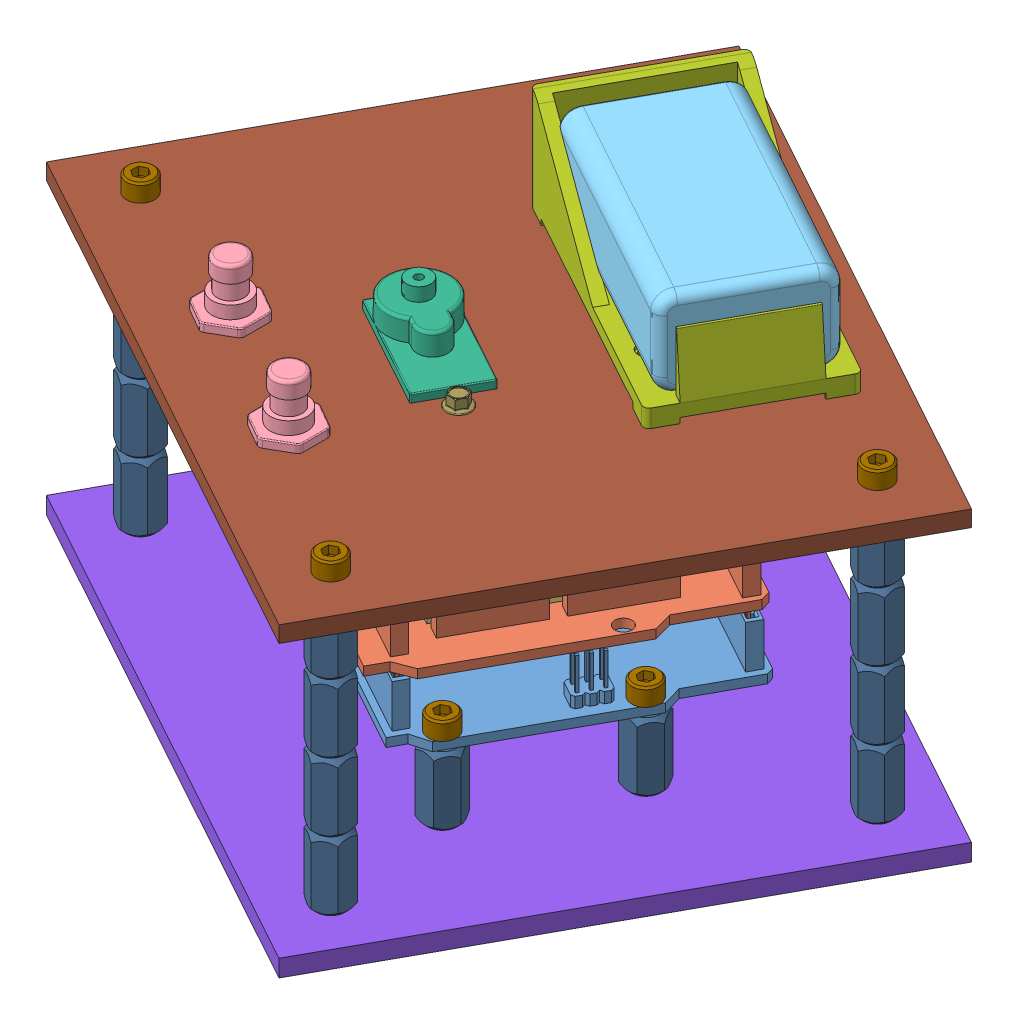
SolidWorks assembly Assembly FinalV2, configuration Default. Lengths in mm.
Overall size (142.18 79.59 136.27).
50 component instances, 12 part files, 102 mates.
Components (placement in the parent):
- ArduinoUno-2: ArduinoUno [Default] at (-58.3842 6.7583 120.4555) x (0.876025 0 0.482266) z (-0.482266 0 0.876025) size (74.8 12.1 53.3)
- Prototyping Shield-Simple-1: Prototyping Shield-Simple [Default] at (-68.6916 -16.1579 180.3995) x (-0.876025 0 -0.482266) z (0.482266 0 -0.876025) size (68 18.92 56)
  - Arduino Prototyping Shield-1: Arduino Prototyping Shield [Default] at (18.3696 35.0162 55.7334) size (68 18.92 56)
  - MiniBreadboard-Simple-1: MiniBreadboard-Simple [Default] at (16.6696 36.6462 55.7334) x (0 0 1) z (-1 0 0) size (34.6 8.15 45.6)
- Panel Mount Pushbutton-1: Panel Mount Pushbutton [Default] at (-85.6604 36.7333 145.3581) size (9.91 29 11.13)
- Panel Mount Pushbutton-2: Panel Mount Pushbutton [Default] at (-61.5698 36.7333 158.6204) size (9.91 29 11.13)
- 9V Battery 2-1: 9V Battery 2 [Default] at (-29.0026 45.2936 106.7603) x (0.482266 0 -0.876025) z (0 1 0) size (25.91 48.13 16.26)
- Micro Servo FS90R Continuous-1: Micro Servo FS90R Continuous [Valor predeterminado] at (-61.5234 42.8583 132.3784) x (0.876025 0 0.482266) z (-0.482266 0 0.876025) size (32 29 12)
- 9V Battery Holder-2: 9V Battery Holder [Default] at (-44.7152 48.8583 99.4932) x (0.876025 0 0.482266) z (0 1 0) size (53.5 30 19.31)
- Acrylic-1: Acrylic [Default] at (-56.2866 -9.1217 122.8659) x (0.876025 0 0.482266) z (-0.482266 0 0.876025) size (110 3.18 95)
- socket head cap screw_ai-6: socket head cap screw_ai [HX-SHCS 0.125-44x0.25x0.25-N] at (-86.6754 -12.2967 132.4484) x (0 1 0) z (0 0 1) size (9.53 5.21 5.21)
- socket head cap screw_ai-7: socket head cap screw_ai [HX-SHCS 0.125-44x0.25x0.25-N] at (-61.9803 -12.2967 90.9081) x (0 1 0) z (0 0 1) size (9.53 5.21 5.21)
- socket head cap screw_ai-8: socket head cap screw_ai [HX-SHCS 0.125-44x0.25x0.25-N] at (-24.8569 -12.2967 128.8104) x (0 1 0) z (0 0 1) size (9.53 5.21 5.21)
- socket head cap screw_ai-9: socket head cap screw_ai [HX-SHCS 0.125-44x0.25x0.25-N] at (-38.3121 -12.2967 153.2514) x (0 1 0) z (0 0 1) size (9.53 5.21 5.21)
- 25x.5 Aluminum Hex Female Female Standoff-1: 25x.5 Aluminum Hex Female Female Standoff [Default] at (-61.9803 0.4083 90.9081) x (-0.837169 0 -0.546944) z (0 -1 0) size (6.35 8.06 12.7)
- 25x.5 Aluminum Hex Female Female Standoff-2: 25x.5 Aluminum Hex Female Female Standoff [Default] at (-86.6754 0.4083 132.4484) x (-0.837169 0 -0.546944) z (0 -1 0) size (6.35 8.06 12.7)
- 25x.5 Aluminum Hex Female Female Standoff-3: 25x.5 Aluminum Hex Female Female Standoff [Default] at (-38.3121 0.4083 153.2514) x (-0.837169 0 -0.546944) z (0 -1 0) size (6.35 8.06 12.7)
- 25x.5 Aluminum Hex Female Female Standoff-4: 25x.5 Aluminum Hex Female Female Standoff [Default] at (-34.9505 0.4083 177.4188) x (1 0 0) z (0 -1 0) size (6.35 8.06 12.7)
- 25x.5 Aluminum Hex Female Female Standoff-5: 25x.5 Aluminum Hex Female Female Standoff [Default] at (-24.8569 0.4083 128.8104) x (-0.837169 0 -0.546944) z (0 -1 0) size (6.35 8.06 12.7)
- socket head cap screw_ai-11: socket head cap screw_ai [HX-SHCS 0.125-44x0.25x0.25-N] at (-24.8569 11.5333 128.8104) x (0 -1 0) z (0.546944 0 -0.837169) size (9.53 5.21 5.21)
- socket head cap screw_ai-12: socket head cap screw_ai [HX-SHCS 0.125-44x0.25x0.25-N] at (-38.3121 11.5333 153.2514) x (0 -1 0) z (0.546944 0 -0.837169) size (9.53 5.21 5.21)
- socket head cap screw_ai-13: socket head cap screw_ai [HX-SHCS 0.125-44x0.25x0.25-N] at (-86.6754 11.5333 132.4484) x (0 -1 0) z (0.546944 0 -0.837169) size (9.53 5.21 5.21)
- socket head cap screw_ai-14: socket head cap screw_ai [HX-SHCS 0.125-44x0.25x0.25-N] at (-61.9803 11.5333 90.9081) x (0 -1 0) z (0.546944 0 -0.837169) size (9.53 5.21 5.21)
- socket head cap screw_ai-17: socket head cap screw_ai [HX-SHCS 0.125-44x0.25x0.25-N] at (-61.4854 15.6833 91.0663) x (0 1 0) z (0 0 1) size (9.53 5.21 5.21)
- socket head cap screw_ai-18: socket head cap screw_ai [HX-SHCS 0.125-44x0.25x0.25-N] at (-34.9505 -12.2967 177.4188) x (0 1 0) z (0 0 1) size (9.53 5.21 5.21)
- socket head cap screw_ai-19: socket head cap screw_ai [HX-SHCS 0.125-44x0.25x0.25-N] at (1.2195 -12.2967 111.717) x (0 1 0) z (0 0 1) size (9.53 5.21 5.21)
- socket head cap screw_ai-20: socket head cap screw_ai [HX-SHCS 0.125-44x0.25x0.25-N] at (-77.6228 -12.2967 68.313) x (0 1 0) z (0 0 1) size (9.53 5.21 5.21)
- socket head cap screw_ai-21: socket head cap screw_ai [HX-SHCS 0.125-44x0.25x0.25-N] at (-113.7927 -12.2967 134.0149) x (0 1 0) z (0 0 1) size (9.53 5.21 5.21)
- 25x.5 Aluminum Hex Female Female Standoff-6: 25x.5 Aluminum Hex Female Female Standoff [Default] at (1.2195 0.4083 111.717) x (1 0 0) z (0 -1 0) size (6.35 8.06 12.7)
- 25x.5 Aluminum Hex Female Female Standoff-7: 25x.5 Aluminum Hex Female Female Standoff [Default] at (-113.7927 0.4083 134.0149) x (1 0 0) z (0 -1 0) size (6.35 8.06 12.7)
- 25x.5 Aluminum Hex Female Female Standoff-8: 25x.5 Aluminum Hex Female Female Standoff [Default] at (-77.6228 0.4083 68.313) x (1 0 0) z (0 -1 0) size (6.35 8.06 12.7)
- 25x.5 Aluminum Hex Female Female Standoff-9: 25x.5 Aluminum Hex Female Female Standoff [Default] at (-34.9505 38.5083 177.4188) x (1 0 0) z (0 -1 0) size (6.35 8.06 12.7)
- 25x.5 Aluminum Hex Female Female Standoff-10: 25x.5 Aluminum Hex Female Female Standoff [Default] at (1.2195 25.8083 111.717) x (1 0 0) z (0 -1 0) size (6.35 8.06 12.7)
- 25x.5 Aluminum Hex Female Female Standoff-11: 25x.5 Aluminum Hex Female Female Standoff [Default] at (-34.9505 13.1083 177.4188) x (1 0 0) z (0 -1 0) size (6.35 8.06 12.7)
- 25x.5 Aluminum Hex Female Female Standoff-12: 25x.5 Aluminum Hex Female Female Standoff [Default] at (1.2195 13.1083 111.717) x (1 0 0) z (0 -1 0) size (6.35 8.06 12.7)
- 25x.5 Aluminum Hex Female Female Standoff-13: 25x.5 Aluminum Hex Female Female Standoff [Default] at (-34.9505 25.8083 177.4188) x (1 0 0) z (0 -1 0) size (6.35 8.06 12.7)
- 25x.5 Aluminum Hex Female Female Standoff-15: 25x.5 Aluminum Hex Female Female Standoff [Default] at (1.2195 38.5083 111.717) x (1 0 0) z (0 -1 0) size (6.35 8.06 12.7)
- 25x.5 Aluminum Hex Female Female Standoff-16: 25x.5 Aluminum Hex Female Female Standoff [Default] at (-113.7927 25.8083 134.0149) x (1 0 0) z (0 -1 0) size (6.35 8.06 12.7)
- 25x.5 Aluminum Hex Female Female Standoff-17: 25x.5 Aluminum Hex Female Female Standoff [Default] at (-113.7927 38.5083 134.0149) x (1 0 0) z (0 -1 0) size (6.35 8.06 12.7)
- 25x.5 Aluminum Hex Female Female Standoff-18: 25x.5 Aluminum Hex Female Female Standoff [Default] at (-77.6228 25.8083 68.313) x (1 0 0) z (0 -1 0) size (6.35 8.06 12.7)
- 25x.5 Aluminum Hex Female Female Standoff-19: 25x.5 Aluminum Hex Female Female Standoff [Default] at (-77.6228 13.1083 68.313) x (1 0 0) z (0 -1 0) size (6.35 8.06 12.7)
- 25x.5 Aluminum Hex Female Female Standoff-20: 25x.5 Aluminum Hex Female Female Standoff [Default] at (-113.7927 13.1083 134.0149) x (1 0 0) z (0 -1 0) size (6.35 8.06 12.7)
- 25x.5 Aluminum Hex Female Female Standoff-21: 25x.5 Aluminum Hex Female Female Standoff [Default] at (-77.6228 38.5083 68.313) x (1 0 0) z (0 -1 0) size (6.35 8.06 12.7)
- Topv4-1: Topv4 [Default] at (-56.2866 44.8583 122.8659) x (0.876025 0 0.482266) z (-0.482266 0 0.876025) size (110 3 95)
- socket head cap screw_ai-22: socket head cap screw_ai [HX-SHCS 0.125-44x0.25x0.25-N] at (-34.9505 51.0333 177.4188) x (0 -1 0) z (0.546944 0 -0.837169) size (9.53 5.21 5.21)
- socket head cap screw_ai-23: socket head cap screw_ai [HX-SHCS 0.125-44x0.25x0.25-N] at (1.2195 51.0333 111.717) x (0 -1 0) z (0.546944 0 -0.837169) size (9.53 5.21 5.21)
- socket head cap screw_ai-24: socket head cap screw_ai [HX-SHCS 0.125-44x0.25x0.25-N] at (-77.6228 51.0333 68.313) x (0 -1 0) z (0.546944 0 -0.837169) size (9.53 5.21 5.21)
- socket head cap screw_ai-25: socket head cap screw_ai [HX-SHCS 0.125-44x0.25x0.25-N] at (-113.7927 51.0333 134.0149) x (0 -1 0) z (0.546944 0 -0.837169) size (9.53 5.21 5.21)
- hex flange machine screw_am-1: hex flange machine screw_am [B18.6.7M - M2 x 0.4 x 6 Indented HFMS --6N] at (-73.4592 50.0583 125.8075) x (0 -1 0) z (0 0 1) size (8.2 4.5 4.5)
- hex flange machine screw_am-2: hex flange machine screw_am [B18.6.7M - M2 x 0.4 x 6 Indented HFMS --6N] at (-49.5876 50.0583 138.9493) x (0 -1 0) z (0 0 1) size (8.2 4.5 4.5)
Mates (geometry in assembly coordinates):
- Coincident11: coincident anti-aligned: plane of ArduinoUno-2 through (-89.9996 18.8583 96.6011) normal (0 1 0); plane of Prototyping Shield-Simple-1/Arduino Prototyping Shield-1 through (-74.1869 18.8583 81.7909) normal (0 -1 0)
- Coincident12: coincident anti-aligned: plane of ArduinoUno-2 through (-43.5141 16.3583 156.8944) normal (0.482266 0 -0.876025); plane of Prototyping Shield-Simple-1/Arduino Prototyping Shield-1 through (-43.5141 10.1083 156.8944) normal (-0.482266 0 0.876025)
- Coincident13: coincident anti-aligned: plane of ArduinoUno-2 through (-43.5141 16.3583 156.8944) normal (-0.876025 0 -0.482266); plane of Prototyping Shield-Simple-1/Arduino Prototyping Shield-1 through (-43.2729 10.1083 156.4564) normal (0.876025 0 0.482266)
- Parallel1: parallel aligned: plane of ArduinoUno-2 through (-99.6631 8.3583 127.0107) normal (-0.876025 0 -0.482266); plane of Prototyping Shield-Simple-1/Arduino Prototyping Shield-1 through (-101.1938 20.4883 130.8483) normal (-0.876025 0 -0.482266)
- Coincident15: coincident anti-aligned: plane of 9V Battery 2-1 through (-29.2808 67.2977 122.7773) normal (0.876025 0 0.482266); plane of 9V Battery Holder-2 through (-27.8562 59.1697 120.1895) normal (-0.876025 0 -0.482266)
- Concentric1: concentric anti-aligned: cylinder of 9V Battery 2-1 through (-59.0217 59.1697 84.3685) axis (0.876025 0 0.482266) radius 2.921; cylinder of 9V Battery Holder-2 through (-60.4335 59.1697 83.5913) axis (-0.876025 0 -0.482266) radius 2.5
- Concentric7: concentric anti-aligned: cylinder of Acrylic-1 through (-86.6754 -9.1217 132.4484) axis (0 1 0) radius 1.6; cylinder of socket head cap screw_ai-6 through (-86.6754 -44.0467 132.4484) axis (0 -1 0) radius 2.6035
- Coincident21: coincident anti-aligned: plane of Acrylic-1 through (-56.2866 -9.1217 122.8659) normal (0 -1 0); plane of socket head cap screw_ai-6 through (-89.2789 -9.1217 132.4484) normal (0 1 0)
- Concentric8: concentric anti-aligned: cylinder of Acrylic-1 through (-61.9803 -9.1217 90.9081) axis (0 1 0) radius 1.6; cylinder of socket head cap screw_ai-7 through (-61.9803 -44.0467 90.9081) axis (0 -1 0) radius 2.6035
- Coincident22: coincident anti-aligned: plane of Acrylic-1 through (-56.2866 -9.1217 122.8659) normal (0 -1 0); plane of socket head cap screw_ai-7 through (-64.5838 -9.1217 90.9081) normal (0 1 0)
- Concentric91: concentric anti-aligned: cylinder of Acrylic-1 through (-24.8569 -9.1217 128.8104) axis (0 1 0) radius 1.6; cylinder of socket head cap screw_ai-8 through (-24.8569 -44.0467 128.8104) axis (0 -1 0) radius 2.6035
- Coincident231: coincident anti-aligned: plane of Acrylic-1 through (-56.2866 -9.1217 122.8659) normal (0 -1 0); plane of socket head cap screw_ai-8 through (-27.4604 -9.1217 128.8104) normal (0 1 0)
- Concentric10: concentric anti-aligned: cylinder of Acrylic-1 through (-38.3121 -9.1217 153.2514) axis (0 1 0) radius 1.6; cylinder of socket head cap screw_ai-9 through (-38.3121 -44.0467 153.2514) axis (0 -1 0) radius 2.6035
- Coincident24: coincident anti-aligned: plane of Acrylic-1 through (-56.2866 -9.1217 122.8659) normal (0 -1 0); plane of socket head cap screw_ai-9 through (-40.9156 -9.1217 153.2514) normal (0 1 0)
- Concentric12: concentric aligned: cylinder of ArduinoUno-2 through (-24.8569 8.3583 128.8104) axis (0 -1 0) radius 1.6; cylinder of socket head cap screw_ai-8 through (-24.8569 -44.0467 128.8104) axis (0 -1 0) radius 1.5875
- Concentric13: concentric aligned: cylinder of ArduinoUno-2 through (-38.3121 8.3583 153.2514) axis (0 -1 0) radius 1.6; cylinder of socket head cap screw_ai-9 through (-38.3121 -44.0467 153.2514) axis (0 -1 0) radius 1.5875
- Concentric15: concentric aligned: cylinder of socket head cap screw_ai-6 through (-86.6754 -44.0467 132.4484) axis (0 -1 0) radius 1.5875; cylinder of 25x.5 Aluminum Hex Female Female Standoff-2 through (-86.6754 -5.9417 132.4484) axis (0 -1 0) radius 1.0287
- Coincident25: coincident anti-aligned: plane of Acrylic-1 through (-56.2866 -5.9417 122.8659) normal (0 1 0); plane of 25x.5 Aluminum Hex Female Female Standoff-2 through (-86.6754 -5.9417 132.4484) normal (0 -1 0)
- Concentric16: concentric aligned: cylinder of socket head cap screw_ai-9 through (-38.3121 -44.0467 153.2514) axis (0 -1 0) radius 1.5875; cylinder of 25x.5 Aluminum Hex Female Female Standoff-3 through (-38.3121 -5.9417 153.2514) axis (0 -1 0) radius 1.0287
- Coincident26: coincident aligned: plane of Acrylic-1 through (-56.2866 -5.9417 122.8659) normal (0 1 0); circle of 25x.5 Aluminum Hex Female Female Standoff-3
- Concentric17: concentric aligned: cylinder of socket head cap screw_ai-8 through (-24.8569 -44.0467 128.8104) axis (0 -1 0) radius 1.5875; cylinder of 25x.5 Aluminum Hex Female Female Standoff-5 through (-24.8569 -5.9417 128.8104) axis (0 -1 0) radius 1.0287
- Coincident27: coincident anti-aligned: plane of Acrylic-1 through (-56.2866 -5.9417 122.8659) normal (0 1 0); plane of 25x.5 Aluminum Hex Female Female Standoff-5 through (-24.8569 -5.9417 128.8104) normal (0 -1 0)
- Concentric18: concentric aligned: cylinder of socket head cap screw_ai-7 through (-61.9803 -44.0467 90.9081) axis (0 -1 0) radius 1.5875; cylinder of 25x.5 Aluminum Hex Female Female Standoff-1 through (-61.9803 -5.9417 90.9081) axis (0 -1 0) radius 1.0287
- Coincident28: coincident anti-aligned: plane of Acrylic-1 through (-56.2866 -5.9417 122.8659) normal (0 1 0); plane of 25x.5 Aluminum Hex Female Female Standoff-1 through (-61.9803 -5.9417 90.9081) normal (0 -1 0)
- Coincident29: coincident anti-aligned: plane of ArduinoUno-2 through (-16.623 6.7583 113.0242) normal (0 -1 0); plane of 25x.5 Aluminum Hex Female Female Standoff-2 through (-86.6754 6.7583 132.4484) normal (0 1 0)
- Concentric191: concentric anti-aligned: cylinder of ArduinoUno-2 through (-24.8569 8.3583 128.8104) axis (0 -1 0) radius 1.6; cylinder of socket head cap screw_ai-11 through (-24.8569 43.2833 128.8104) axis (0 1 0) radius 2.6035
- Coincident301: coincident anti-aligned: plane of ArduinoUno-2 through (-16.623 8.3583 113.0242) normal (0 1 0); plane of socket head cap screw_ai-11 through (-27.0365 8.3583 127.3864) normal (0 -1 0)
- Concentric201: concentric anti-aligned: cylinder of ArduinoUno-2 through (-38.3121 8.3583 153.2514) axis (0 -1 0) radius 1.6; cylinder of socket head cap screw_ai-12 through (-38.3121 43.2833 153.2514) axis (0 1 0) radius 2.6035
- Coincident311: coincident anti-aligned: plane of ArduinoUno-2 through (-16.623 8.3583 113.0242) normal (0 1 0); plane of socket head cap screw_ai-12 through (-40.4917 8.3583 151.8275) normal (0 -1 0)
- Concentric211: concentric anti-aligned: cylinder of ArduinoUno-2 through (-86.6754 8.3583 132.4484) axis (0 -1 0) radius 1.6; cylinder of socket head cap screw_ai-13 through (-86.6754 43.2833 132.4484) axis (0 1 0) radius 2.6035
- Coincident321: coincident anti-aligned: plane of ArduinoUno-2 through (-16.623 8.3583 113.0242) normal (0 1 0); plane of socket head cap screw_ai-13 through (-88.855 8.3583 131.0245) normal (0 -1 0)
- Concentric221: concentric anti-aligned: cylinder of ArduinoUno-2 through (-61.9803 8.3583 90.9081) axis (0 -1 0) radius 1.6; cylinder of socket head cap screw_ai-14 through (-61.9803 43.2833 90.9081) axis (0 1 0) radius 2.6035
- Coincident331: coincident anti-aligned: plane of ArduinoUno-2 through (-16.623 8.3583 113.0242) normal (0 1 0); plane of socket head cap screw_ai-14 through (-64.1599 8.3583 89.4841) normal (0 -1 0)
- Concentric241: concentric anti-aligned: cylinder of Prototyping Shield-Simple-1/Arduino Prototyping Shield-1 through (-61.4854 10.1083 91.0663) axis (0 1 0) radius 1.6; cylinder of socket head cap screw_ai-17 through (-61.4854 -16.0667 91.0663) axis (0 -1 0) radius 2.6035
- Coincident351: coincident anti-aligned: plane of Prototyping Shield-Simple-1/Arduino Prototyping Shield-1 through (-74.1869 18.8583 81.7909) normal (0 -1 0); plane of socket head cap screw_ai-17 through (-64.0889 18.8583 91.0663) normal (0 1 0)
- Concentric2431: concentric anti-aligned: cylinder of Acrylic-1 through (-34.9505 -15.9417 177.4188) axis (0 1 0) radius 1.6; cylinder of socket head cap screw_ai-18 through (-34.9505 -44.0467 177.4188) axis (0 -1 0) radius 2.6035
- Coincident3531: coincident anti-aligned: plane of Acrylic-1 through (-56.2866 -9.1217 122.8659) normal (0 -1 0); plane of socket head cap screw_ai-18 through (-37.554 -9.1217 177.4188) normal (0 1 0)
- Concentric2441: concentric anti-aligned: cylinder of Acrylic-1 through (1.2195 -15.9417 111.717) axis (0 1 0) radius 1.6; cylinder of socket head cap screw_ai-19 through (1.2195 -44.0467 111.717) axis (0 -1 0) radius 2.6035
- Coincident3541: coincident anti-aligned: plane of Acrylic-1 through (-56.2866 -9.1217 122.8659) normal (0 -1 0); plane of socket head cap screw_ai-19 through (-1.384 -9.1217 111.717) normal (0 1 0)
- Concentric2451: concentric anti-aligned: cylinder of Acrylic-1 through (-77.6228 -15.9417 68.313) axis (0 1 0) radius 1.6; cylinder of socket head cap screw_ai-20 through (-77.6228 -44.0467 68.313) axis (0 -1 0) radius 2.6035
- Coincident3551: coincident anti-aligned: plane of Acrylic-1 through (-56.2866 -9.1217 122.8659) normal (0 -1 0); plane of socket head cap screw_ai-20 through (-80.2263 -9.1217 68.313) normal (0 1 0)
- Concentric2461: concentric anti-aligned: cylinder of Acrylic-1 through (-113.7927 -15.9417 134.0149) axis (0 1 0) radius 1.6; cylinder of socket head cap screw_ai-21 through (-113.7927 -44.0467 134.0149) axis (0 -1 0) radius 2.6035
- Coincident3561: coincident anti-aligned: plane of Acrylic-1 through (-56.2866 -9.1217 122.8659) normal (0 -1 0); plane of socket head cap screw_ai-21 through (-116.3962 -9.1217 134.0149) normal (0 1 0)
- Coincident357: coincident anti-aligned: plane of Acrylic-1 through (-56.2866 -5.9417 122.8659) normal (0 1 0); plane of 25x.5 Aluminum Hex Female Female Standoff-4 through (-34.9505 -5.9417 177.4188) normal (0 -1 0)
- Concentric247: concentric aligned: cylinder of 25x.5 Aluminum Hex Female Female Standoff-4 through (-34.9505 -5.9417 177.4188) axis (0 -1 0) radius 1.0287; cylinder of socket head cap screw_ai-18 through (-34.9505 -44.0467 177.4188) axis (0 -1 0) radius 1.5875
- Coincident359: coincident anti-aligned: plane of Acrylic-1 through (-56.2866 -5.9417 122.8659) normal (0 1 0); plane of 25x.5 Aluminum Hex Female Female Standoff-6 through (1.2195 -5.9417 111.717) normal (0 -1 0)
- Concentric248: concentric aligned: cylinder of socket head cap screw_ai-19 through (1.2195 -44.0467 111.717) axis (0 -1 0) radius 1.5875; cylinder of 25x.5 Aluminum Hex Female Female Standoff-6 through (1.2195 -5.9417 111.717) axis (0 -1 0) radius 1.0287
- Coincident360: coincident anti-aligned: plane of Acrylic-1 through (-56.2866 -5.9417 122.8659) normal (0 1 0); plane of 25x.5 Aluminum Hex Female Female Standoff-7 through (-113.7927 -5.9417 134.0149) normal (0 -1 0)
- Concentric249: concentric aligned: cylinder of socket head cap screw_ai-21 through (-113.7927 -44.0467 134.0149) axis (0 -1 0) radius 1.5875; cylinder of 25x.5 Aluminum Hex Female Female Standoff-7 through (-113.7927 -5.9417 134.0149) axis (0 -1 0) radius 1.0287
- Coincident361: coincident anti-aligned: plane of Acrylic-1 through (-56.2866 -5.9417 122.8659) normal (0 1 0); plane of 25x.5 Aluminum Hex Female Female Standoff-8 through (-77.6228 -5.9417 68.313) normal (0 -1 0)
- Concentric250: concentric aligned: cylinder of socket head cap screw_ai-20 through (-77.6228 -44.0467 68.313) axis (0 -1 0) radius 1.5875; cylinder of 25x.5 Aluminum Hex Female Female Standoff-8 through (-77.6228 -5.9417 68.313) axis (0 -1 0) radius 1.0287
- Coincident362: coincident anti-aligned: plane of 25x.5 Aluminum Hex Female Female Standoff-4 through (-34.9505 6.7583 177.4188) normal (0 1 0); plane of 25x.5 Aluminum Hex Female Female Standoff-11 through (-34.9505 6.7583 177.4188) normal (0 -1 0)
- Concentric251: concentric aligned: cylinder of 25x.5 Aluminum Hex Female Female Standoff-4 through (-34.9505 -5.9417 177.4188) axis (0 -1 0) radius 1.0287; cylinder of 25x.5 Aluminum Hex Female Female Standoff-11 through (-34.9505 6.7583 177.4188) axis (0 -1 0) radius 1.0287
- Coincident363: coincident anti-aligned: plane of 25x.5 Aluminum Hex Female Female Standoff-11 through (-34.9505 19.4583 177.4188) normal (0 1 0); plane of 25x.5 Aluminum Hex Female Female Standoff-13 through (-34.9505 19.4583 177.4188) normal (0 -1 0)
- Concentric252: concentric aligned: cylinder of 25x.5 Aluminum Hex Female Female Standoff-11 through (-34.9505 6.7583 177.4188) axis (0 -1 0) radius 1.0287; cylinder of 25x.5 Aluminum Hex Female Female Standoff-13 through (-34.9505 19.4583 177.4188) axis (0 -1 0) radius 1.0287
- Coincident365: coincident anti-aligned: plane of 25x.5 Aluminum Hex Female Female Standoff-9 through (-34.9505 32.1583 177.4188) normal (0 -1 0); plane of 25x.5 Aluminum Hex Female Female Standoff-13 through (-34.9505 32.1583 177.4188) normal (0 1 0)
- Concentric253: concentric aligned: cylinder of 25x.5 Aluminum Hex Female Female Standoff-9 through (-34.9505 32.1583 177.4188) axis (0 -1 0) radius 1.0287; cylinder of 25x.5 Aluminum Hex Female Female Standoff-13 through (-34.9505 19.4583 177.4188) axis (0 -1 0) radius 1.0287
- Coincident366: coincident anti-aligned: plane of 25x.5 Aluminum Hex Female Female Standoff-6 through (1.2195 6.7583 111.717) normal (0 1 0); plane of 25x.5 Aluminum Hex Female Female Standoff-12 through (1.2195 6.7583 111.717) normal (0 -1 0)
- Concentric254: concentric aligned: cylinder of 25x.5 Aluminum Hex Female Female Standoff-6 through (1.2195 -5.9417 111.717) axis (0 -1 0) radius 1.0287; cylinder of 25x.5 Aluminum Hex Female Female Standoff-12 through (1.2195 6.7583 111.717) axis (0 -1 0) radius 1.0287
- Concentric255: concentric aligned: cylinder of 25x.5 Aluminum Hex Female Female Standoff-10 through (1.2195 19.4583 111.717) axis (0 -1 0) radius 1.0287; cylinder of 25x.5 Aluminum Hex Female Female Standoff-12 through (1.2195 6.7583 111.717) axis (0 -1 0) radius 1.0287
- Coincident367: coincident anti-aligned: plane of 25x.5 Aluminum Hex Female Female Standoff-10 through (1.2195 19.4583 111.717) normal (0 -1 0); plane of 25x.5 Aluminum Hex Female Female Standoff-12 through (1.2195 19.4583 111.717) normal (0 1 0)
- Coincident368: coincident anti-aligned: plane of 25x.5 Aluminum Hex Female Female Standoff-10 through (1.2195 32.1583 111.717) normal (0 1 0); plane of 25x.5 Aluminum Hex Female Female Standoff-15 through (1.2195 32.1583 111.717) normal (0 -1 0)
- Concentric256: concentric aligned: cylinder of 25x.5 Aluminum Hex Female Female Standoff-10 through (1.2195 19.4583 111.717) axis (0 -1 0) radius 1.0287; cylinder of 25x.5 Aluminum Hex Female Female Standoff-15 through (1.2195 32.1583 111.717) axis (0 -1 0) radius 1.0287
- Coincident369: coincident anti-aligned: plane of 25x.5 Aluminum Hex Female Female Standoff-8 through (-77.6228 6.7583 68.313) normal (0 1 0); plane of 25x.5 Aluminum Hex Female Female Standoff-19 through (-77.6228 6.7583 68.313) normal (0 -1 0)
- Concentric257: concentric aligned: cylinder of 25x.5 Aluminum Hex Female Female Standoff-8 through (-77.6228 -5.9417 68.313) axis (0 -1 0) radius 1.0287; cylinder of 25x.5 Aluminum Hex Female Female Standoff-19 through (-77.6228 6.7583 68.313) axis (0 -1 0) radius 1.0287
- Coincident370: coincident anti-aligned: plane of 25x.5 Aluminum Hex Female Female Standoff-18 through (-77.6228 19.4583 68.313) normal (0 -1 0); plane of 25x.5 Aluminum Hex Female Female Standoff-19 through (-77.6228 19.4583 68.313) normal (0 1 0)
- Concentric258: concentric aligned: cylinder of 25x.5 Aluminum Hex Female Female Standoff-18 through (-77.6228 19.4583 68.313) axis (0 -1 0) radius 1.0287; cylinder of 25x.5 Aluminum Hex Female Female Standoff-19 through (-77.6228 6.7583 68.313) axis (0 -1 0) radius 1.0287
- Coincident371: coincident anti-aligned: plane of 25x.5 Aluminum Hex Female Female Standoff-18 through (-77.6228 32.1583 68.313) normal (0 1 0); plane of 25x.5 Aluminum Hex Female Female Standoff-21 through (-77.6228 32.1583 68.313) normal (0 -1 0)
- Concentric259: concentric aligned: cylinder of 25x.5 Aluminum Hex Female Female Standoff-18 through (-77.6228 19.4583 68.313) axis (0 -1 0) radius 1.0287; cylinder of 25x.5 Aluminum Hex Female Female Standoff-21 through (-77.6228 32.1583 68.313) axis (0 -1 0) radius 1.0287
- Coincident372: coincident anti-aligned: plane of 25x.5 Aluminum Hex Female Female Standoff-7 through (-113.7927 6.7583 134.0149) normal (0 1 0); plane of 25x.5 Aluminum Hex Female Female Standoff-20 through (-113.7927 6.7583 134.0149) normal (0 -1 0)
- Concentric260: concentric aligned: cylinder of 25x.5 Aluminum Hex Female Female Standoff-7 through (-113.7927 -5.9417 134.0149) axis (0 -1 0) radius 1.0287; cylinder of 25x.5 Aluminum Hex Female Female Standoff-20 through (-113.7927 6.7583 134.0149) axis (0 -1 0) radius 1.0287
- Coincident373: coincident anti-aligned: plane of 25x.5 Aluminum Hex Female Female Standoff-16 through (-113.7927 19.4583 134.0149) normal (0 -1 0); plane of 25x.5 Aluminum Hex Female Female Standoff-20 through (-113.7927 19.4583 134.0149) normal (0 1 0)
- Concentric261: concentric aligned: cylinder of 25x.5 Aluminum Hex Female Female Standoff-16 through (-113.7927 19.4583 134.0149) axis (0 -1 0) radius 1.0287; cylinder of 25x.5 Aluminum Hex Female Female Standoff-20 through (-113.7927 6.7583 134.0149) axis (0 -1 0) radius 1.0287
- Coincident374: coincident anti-aligned: plane of 25x.5 Aluminum Hex Female Female Standoff-16 through (-113.7927 32.1583 134.0149) normal (0 1 0); plane of 25x.5 Aluminum Hex Female Female Standoff-17 through (-113.7927 32.1583 134.0149) normal (0 -1 0)
- Concentric262: concentric aligned: cylinder of 25x.5 Aluminum Hex Female Female Standoff-16 through (-113.7927 19.4583 134.0149) axis (0 -1 0) radius 1.0287; cylinder of 25x.5 Aluminum Hex Female Female Standoff-17 through (-113.7927 32.1583 134.0149) axis (0 -1 0) radius 1.0287
- Coincident375: coincident anti-aligned: plane of 25x.5 Aluminum Hex Female Female Standoff-9 through (-34.9505 44.8583 177.4188) normal (0 1 0); plane of Topv4-1 through (-56.2866 44.8583 122.8659) normal (0 -1 0)
- Concentric263: concentric anti-aligned: cylinder of 25x.5 Aluminum Hex Female Female Standoff-9 through (-34.9505 32.1583 177.4188) axis (0 -1 0) radius 1.0287; circle of Topv4-1
- Concentric264: concentric anti-aligned: cylinder of 25x.5 Aluminum Hex Female Female Standoff-21 through (-77.6228 32.1583 68.313) axis (0 -1 0) radius 1.0287; circle of Topv4-1
- Concentric2651: concentric aligned: cylinder of Topv4-1 through (-34.9505 44.8583 177.4188) axis (0 1 0) radius 1.6; cylinder of socket head cap screw_ai-22 through (-34.9505 82.7833 177.4188) axis (0 1 0) radius 2.6035
- Coincident3761: coincident anti-aligned: plane of Topv4-1 through (-56.2866 47.8583 122.8659) normal (0 1 0); plane of socket head cap screw_ai-22 through (-37.1301 47.8583 175.9948) normal (0 -1 0)
- Concentric2661: concentric aligned: cylinder of Topv4-1 through (1.2195 44.8583 111.717) axis (0 1 0) radius 1.6; cylinder of socket head cap screw_ai-23 through (1.2195 82.7833 111.717) axis (0 1 0) radius 2.6035
- Coincident3771: coincident anti-aligned: plane of Topv4-1 through (-56.2866 47.8583 122.8659) normal (0 1 0); plane of socket head cap screw_ai-23 through (-0.9601 47.8583 110.293) normal (0 -1 0)
- Concentric2671: concentric aligned: cylinder of Topv4-1 through (-77.6228 44.8583 68.313) axis (0 1 0) radius 1.6; cylinder of socket head cap screw_ai-24 through (-77.6228 82.7833 68.313) axis (0 1 0) radius 2.6035
- Coincident3781: coincident anti-aligned: plane of Topv4-1 through (-56.2866 47.8583 122.8659) normal (0 1 0); plane of socket head cap screw_ai-24 through (-79.8023 47.8583 66.889) normal (0 -1 0)
- Concentric2681: concentric aligned: cylinder of Topv4-1 through (-113.7927 44.8583 134.0149) axis (0 1 0) radius 1.6; cylinder of socket head cap screw_ai-25 through (-113.7927 82.7833 134.0149) axis (0 1 0) radius 2.6035
- Coincident3791: coincident anti-aligned: plane of Topv4-1 through (-56.2866 47.8583 122.8659) normal (0 1 0); plane of socket head cap screw_ai-25 through (-115.9723 47.8583 132.5909) normal (0 -1 0)
- Coincident380: coincident anti-aligned: plane of 9V Battery Holder-2 through (-39.5067 47.8583 90.0321) normal (0 -1 0); plane of Topv4-1 through (-56.2866 47.8583 122.8659) normal (0 1 0)
- Concentric269: concentric aligned: circle of 9V Battery Holder-2; cylinder of Topv4-1 through (-39.5067 47.8583 90.0321) axis (0 -1 0) radius 2
- Concentric270: concentric aligned: circle of 9V Battery Holder-2; cylinder of Topv4-1 through (-37.8301 47.8583 115.4978) axis (0 -1 0) radius 2
- Concentric271: concentric anti-aligned: cylinder of Panel Mount Pushbutton-1 through (-85.6604 36.7333 145.3581) axis (0 -1 0) radius 3.81; cylinder of Topv4-1 through (-85.6604 44.8583 145.3581) axis (0 1 0) radius 4.575
- Coincident381: coincident anti-aligned: plane of Panel Mount Pushbutton-1 through (-85.6604 47.8583 145.3581) normal (0 -1 0); plane of Topv4-1 through (-56.2866 47.8583 122.8659) normal (0 1 0)
- Concentric272: concentric anti-aligned: cylinder of Panel Mount Pushbutton-2 through (-61.5698 36.7333 158.6204) axis (0 -1 0) radius 3.81; cylinder of Topv4-1 through (-61.5698 44.8583 158.6204) axis (0 1 0) radius 4.575
- Coincident382: coincident anti-aligned: plane of Panel Mount Pushbutton-2 through (-61.5698 47.8583 158.6204) normal (0 -1 0); plane of Topv4-1 through (-56.2866 47.8583 122.8659) normal (0 1 0)
- Coincident3805: coincident anti-aligned: plane of Micro Servo FS90R Continuous-1 through (-73.4592 44.8583 125.8075) normal (0 1 0); plane of Topv4-1 through (-56.2866 44.8583 122.8659) normal (0 -1 0)
- Coincident3807: coincident anti-aligned: plane of Micro Servo FS90R Continuous-1 through (-68.4851 26.8583 121.6968) normal (-0.876025 0 -0.482266); plane of Topv4-1 through (-66.1419 37.8583 117.4404) normal (0.876025 0 0.482266)
- Coincident3808: coincident anti-aligned: plane of Micro Servo FS90R Continuous-1 through (-74.2723 26.8583 132.2091) normal (-0.482266 0 0.876025); plane of Topv4-1 through (-64.417 37.8583 137.6346) normal (0.482266 0 -0.876025)
- Concentric26821: concentric aligned: cylinder of Topv4-1 through (-73.4592 37.8583 125.8075) axis (0 1 0) radius 1; cylinder of socket head cap screw_ai-26 through (-73.4592 82.7833 125.8075) axis (0 1 0) radius 2.6035
- Coincident38091: coincident anti-aligned: plane of Topv4-1 through (-56.2866 47.8583 122.8659) normal (0 1 0); plane of socket head cap screw_ai-26 through (-75.6388 47.8583 124.3836) normal (0 -1 0)
- Concentric2684: concentric aligned: cylinder of Topv4-1 through (-73.4592 37.8583 125.8075) axis (0 1 0) radius 1; cylinder of hex flange machine screw_am-1 through (-73.4592 75.4583 125.8075) axis (0 1 0) radius 1
- Coincident3811: coincident anti-aligned: plane of Topv4-1 through (-56.2866 47.8583 122.8659) normal (0 1 0); plane of hex flange machine screw_am-1 through (-72.4592 47.8583 125.8075) normal (0 -1 0)
- Concentric2685: concentric aligned: cylinder of Topv4-1 through (-49.5876 37.8583 138.9493) axis (0 1 0) radius 1; cylinder of hex flange machine screw_am-2 through (-49.5876 75.4583 138.9493) axis (0 1 0) radius 1
- Coincident3812: coincident anti-aligned: plane of Topv4-1 through (-56.2866 47.8583 122.8659) normal (0 1 0); plane of hex flange machine screw_am-2 through (-48.5876 47.8583 138.9493) normal (0 -1 0)
